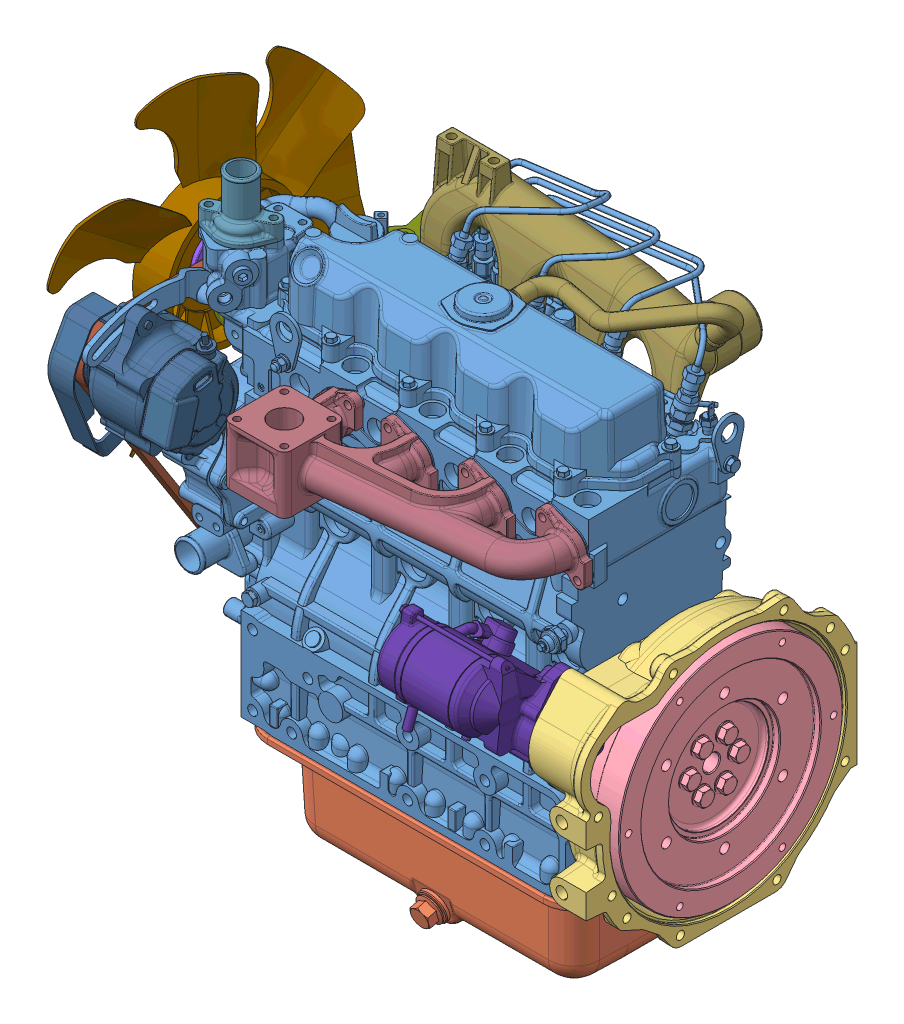
SolidWorks assembly v2203_01891, configuration Default. Lengths in mm.
Overall size (669.39 681.44 494.99).
18 component instances, 18 part files, 3 mates.
Components (placement in the parent):
- CORE_01891-1: CORE_01891 [Default] at origin size (596.01 515.55 494.99)
- OILP_01891-1: OILP_01891 [Default] at origin size (410.6 144 247)
- FWHU_01891-1: FWHU_01891 [Default] at origin size (90.23 313.63 348.46)
- FLWH_01891-1: FLWH_01891 [Default] at origin size (61 275 275)
- PUFD_01891-1: PUFD_01891 [Default] at origin size (40.5 104 104)
- CNUT_01891-1: CNUT_01891 [Default] at origin size (12 53.12 46)
- FANP_01891-1: FANP_01891 [Default] at origin size (51.6 99 99)
- FANC_01891-1: FANC_01891 [Default] at origin size (20.01 72.12 72.11)
- FAN_01891-1: FAN_01891 [Default] at origin size (50.42 403.32 417.06)
- ALTN_01891-1: ALTN_01891 [Default] at origin size (153.25 171.12 110.56)
- VBLT_01891-1: VBLT_01891 [Default] at origin size (13.3 332.62 274.79)
- INMN_01891-1: INMN_01891 [Default] at origin size (386.24 179.55 160.5)
- EXMN_01891-1: EXMN_01891 [Default] at origin size (355.04 75.17 112.05)
- TCOV_01891-1: TCOV_01891 [Default] at origin size (74.25 65 58)
- SPED_01891-1: SPED_01891 [Default] at origin size (61.44 39.2 44.81)
- STOP_01891-1: STOP_01891 [Default] at origin size (38.48 11.5 85.71)
- STRT_01891-1: STRT_01891 [Default] at origin size (194.61 148.21 134.43)
- OILF_01891-1: OILF_01891 [Default] at origin size (97.5 97.5 85.5)
Mates (geometry in assembly coordinates):
- Concentric2: concentric anti-aligned: cylinder of FWHU_01891-1 through (299.5 127.5 128.7478) axis (-1 0 0) radius 5; cylinder of STRT_01891-1 through (299.5 127.5 128.7478) axis (1 0 0) radius 5.5
- Coincident1: coincident aligned: plane of FWHU_01891-1 through (299.5 0 0) normal (1 0 0); plane of STRT_01891-1 through (299.5 75 128.7478) normal (1 0 0)
- Concentric3: concentric anti-aligned: cylinder of FWHU_01891-1 through (224.5 22.5 128.7478) axis (-1 0 0) radius 5; cylinder of STRT_01891-1 through (299.5 22.5 128.7478) axis (1 0 0) radius 5.5
